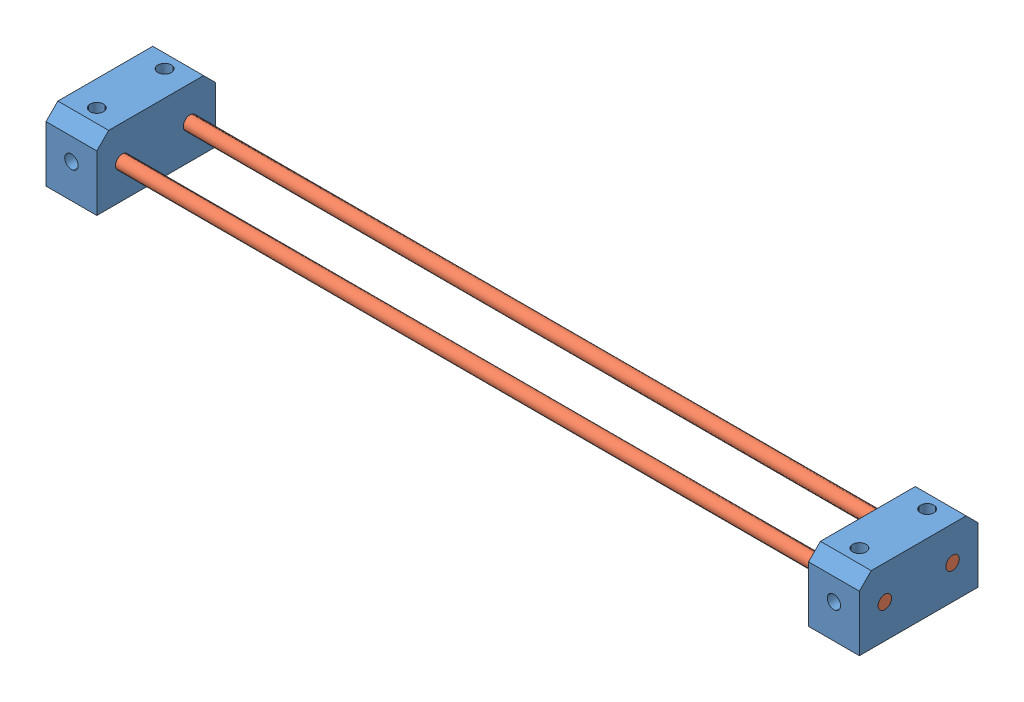
SolidWorks assembly M01, configuration Valor predeterminado. Lengths in mm.
Overall size (480 40 70).
4 component instances, 2 part files, 5 mates.
Components (placement in the parent):
- S02-1: S02 [Valor predeterminado] at (67.124 0.9923 31.879) size (30 40 70)
- S02-2: S02 [Valor predeterminado] at (517.124 0.9923 31.879) size (30 40 70)
- B01-1: B01 [Valor predeterminado] at (292.124 0.9923 51.879) x (0 -0.668888 0.743363) z (-1 0 0) size (7.94 7.94 480)
- B01-2: B01 [Valor predeterminado] at (292.124 0.9923 11.879) x (0 0 1) z (-1 0 0) size (7.94 7.94 480)
Mates (geometry in assembly coordinates):
- Distância1: distance = 420 mm: plane of S02-1 through (82.124 0.9923 31.879) normal (1 0 0); plane of S02-2 through (502.124 0.9923 31.879) normal (-1 0 0)
- Coincidente3: coincident: plane of S02-1 through (82.124 20.9923 66.879) normal (0 0 1); plane of S02-2 through (532.124 20.9923 66.879) normal (0 0 1)
- Coincidente4: coincident: plane of S02-1 through (82.124 20.9923 -3.121) normal (0 1 0); plane of S02-2 through (532.124 20.9923 -3.121) normal (0 1 0)
- Coincidente5: coincident: circle of S02-1; circle of B01-1
- Coincidente6: coincident: circle of S02-2; circle of B01-2
